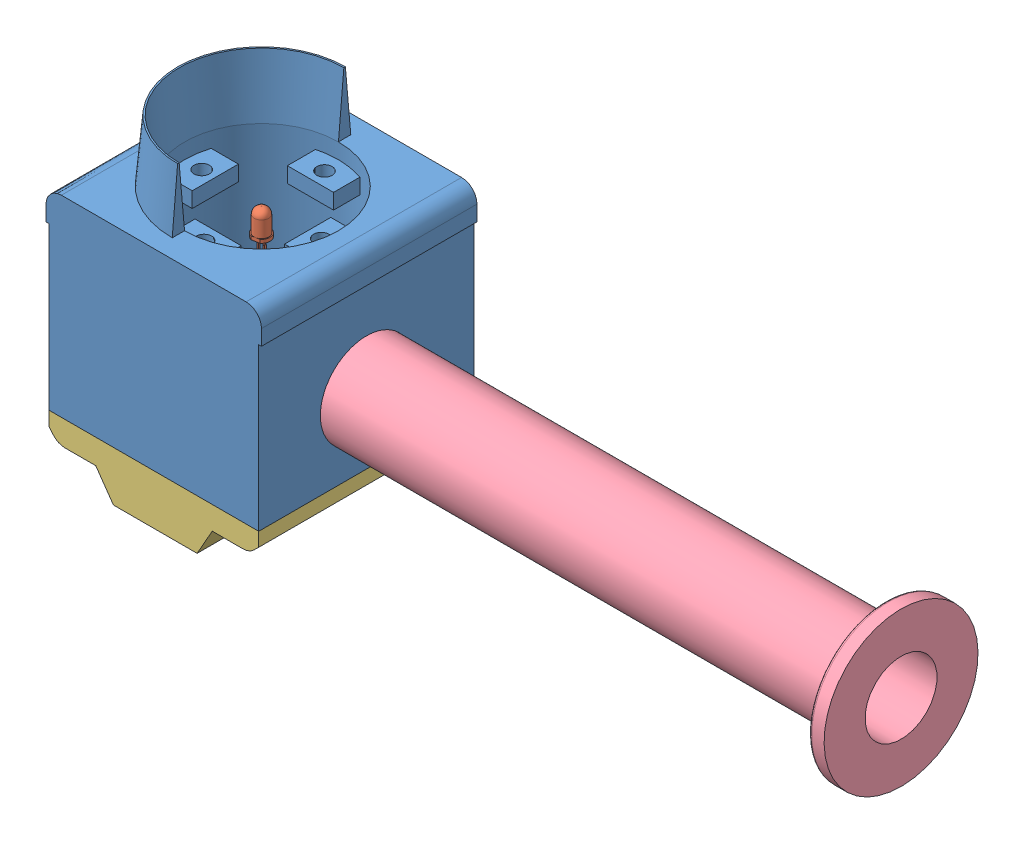
SolidWorks assembly TraficLightAssemwLeg, configuration Default. Lengths in mm.
Overall size (242.75 98.71 70).
5 component instances, 4 part files, 2 mates.
Components (placement in the parent):
- TrafficLightAssem-1: TrafficLightAssem [Default] at (30.1893 58.7835 79.8477) size (70 98.71 70)
  - Body2-1: Body2 [Default] at (-44.4823 8.0715 -33.3061) size (70 82.5 70)
  - LED 5mm-1: LED 5mm [Default] at (-17.3637 18.1433 1.6939) x (-0.183633 0 -0.982995) z (0.982995 0 -0.183633) size (5.2 36.5 5.5)
  - Body1-1: Body1 [Default] at (-44.4823 8.0715 -33.3061) size (68.2 16.21 70)
- New_leg-1: New_leg [Default] at (215.5756 51.0268 81.5416) x (0 -0.328198 0.944609) z (0 -0.944609 -0.328198) size (50 205 50)
Mates (geometry in assembly coordinates):
- Concentric1: concentric aligned: cylinder of TrafficLightAssem-1/Body2-1 through (16.9249 51.0268 81.5416) axis (1 0 0) radius 15; cylinder of New_leg-1 through (215.5756 51.0268 81.5416) axis (1 0 0) radius 15
- Tangent1: tangent anti-aligned: cylinder of TrafficLightAssem-1/LED 5mm-1 through (12.8256 78.0268 81.5416) axis (0 -1 0) radius 2.75; plane of New_leg-1 through (15.5756 51.0268 81.5416) normal (-1 0 0)
